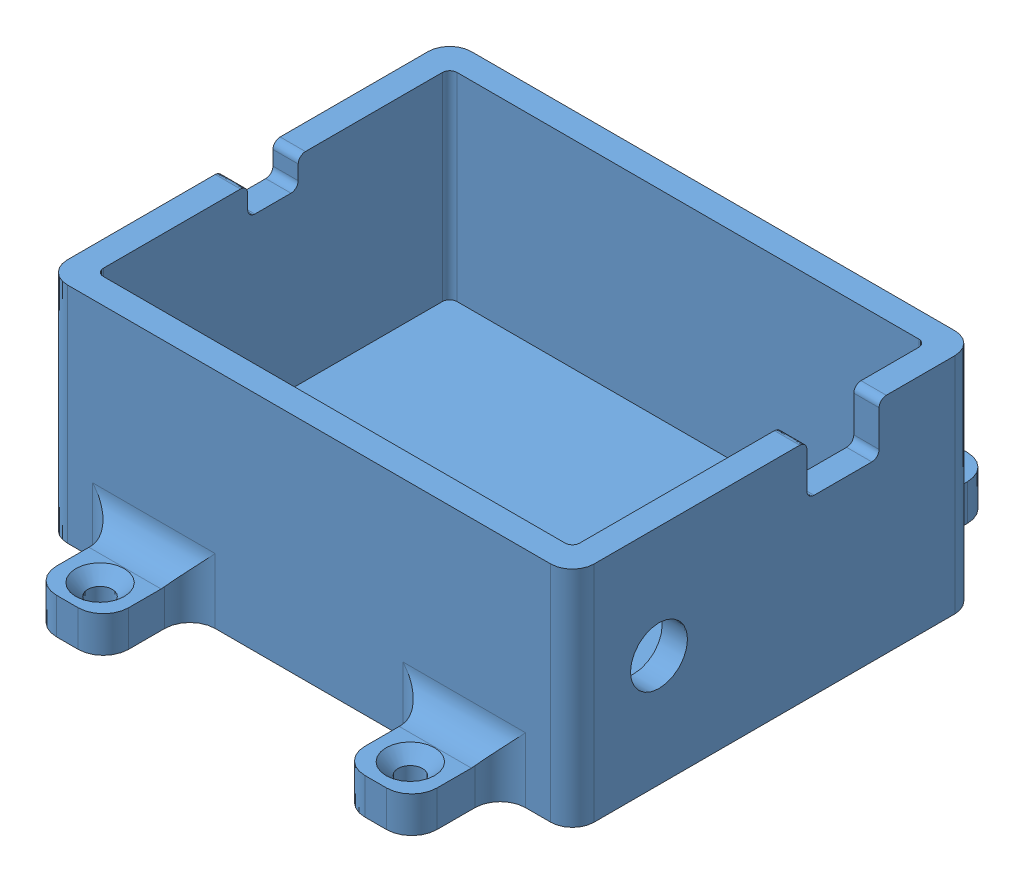
SolidWorks assembly Mont1, configuration Valor predeterminado. Lengths in mm.
Overall size (73 31 80.52).
2 component instances, 2 part files, 0 mates.
Components (placement in the parent):
- Fita_RGB-1: Fita_RGB [Valor predeterminado] at (-19.0584 -25.0023 80.5207) size (73 31 80.52)
- Tampa_RGB-1: Tampa_RGB [Valor predeterminado] at origin
